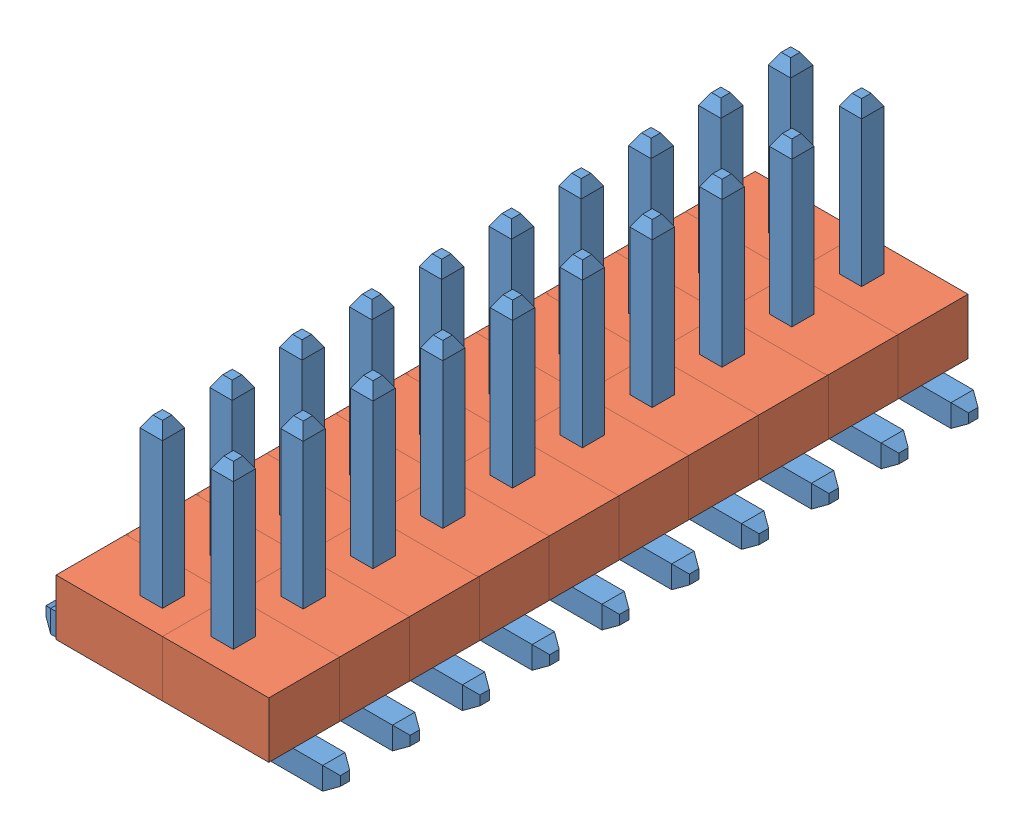
SolidWorks assembly Assem5, configuration Default. Lengths in mm.
Overall size (5.27 4.2 12.52).
60 component instances, 2 part files, 0 mates.
Components (placement in the parent):
- 1_27mm_single_pin_assembled-1: 1_27mm_single_pin_assembled [Default] at (-0.3615 -0.2189 0.4542) size (2.64 4.2 1.27)
  - 1_27mm_pin_right_angle-1: 1_27mm_pin_right_angle [Default] at (-0.7701 -1.6572 -0.2335) size (2.2 4.2 0.4)
  - 1_27mm_plastic_for_pin-1: 1_27mm_plastic_for_pin [Default] at (-0.4526 -1.4572 -0.2335) x (0 0 -1) z (1 0 0) size (1.27 1 1.91)
- 1_27mm_single_pin_assembled-2: 1_27mm_single_pin_assembled [Default] at (-0.3615 -0.2189 -0.7958) size (2.64 4.2 1.27)
  - 1_27mm_pin_right_angle-1: 1_27mm_pin_right_angle [Default] at (-0.7701 -1.6572 -0.2335) size (2.2 4.2 0.4)
  - 1_27mm_plastic_for_pin-1: 1_27mm_plastic_for_pin [Default] at (-0.4526 -1.4572 -0.2335) x (0 0 -1) z (1 0 0) size (1.27 1 1.91)
- 1_27mm_single_pin_assembled-3: 1_27mm_single_pin_assembled [Default] at (-0.3615 -0.2189 -2.0458) size (2.64 4.2 1.27)
  - 1_27mm_pin_right_angle-1: 1_27mm_pin_right_angle [Default] at (-0.7701 -1.6572 -0.2335) size (2.2 4.2 0.4)
  - 1_27mm_plastic_for_pin-1: 1_27mm_plastic_for_pin [Default] at (-0.4526 -1.4572 -0.2335) x (0 0 -1) z (1 0 0) size (1.27 1 1.91)
- 1_27mm_single_pin_assembled-4: 1_27mm_single_pin_assembled [Default] at (-0.3615 -0.2189 -3.2958) size (2.64 4.2 1.27)
  - 1_27mm_pin_right_angle-1: 1_27mm_pin_right_angle [Default] at (-0.7701 -1.6572 -0.2335) size (2.2 4.2 0.4)
  - 1_27mm_plastic_for_pin-1: 1_27mm_plastic_for_pin [Default] at (-0.4526 -1.4572 -0.2335) x (0 0 -1) z (1 0 0) size (1.27 1 1.91)
- 1_27mm_single_pin_assembled-5: 1_27mm_single_pin_assembled [Default] at (-0.3615 -0.2189 -4.5458) size (2.64 4.2 1.27)
  - 1_27mm_pin_right_angle-1: 1_27mm_pin_right_angle [Default] at (-0.7701 -1.6572 -0.2335) size (2.2 4.2 0.4)
  - 1_27mm_plastic_for_pin-1: 1_27mm_plastic_for_pin [Default] at (-0.4526 -1.4572 -0.2335) x (0 0 -1) z (1 0 0) size (1.27 1 1.91)
- 1_27mm_single_pin_assembled-6: 1_27mm_single_pin_assembled [Default] at (-0.3615 -0.2189 -5.7958) size (2.64 4.2 1.27)
  - 1_27mm_pin_right_angle-1: 1_27mm_pin_right_angle [Default] at (-0.7701 -1.6572 -0.2335) size (2.2 4.2 0.4)
  - 1_27mm_plastic_for_pin-1: 1_27mm_plastic_for_pin [Default] at (-0.4526 -1.4572 -0.2335) x (0 0 -1) z (1 0 0) size (1.27 1 1.91)
- 1_27mm_single_pin_assembled-7: 1_27mm_single_pin_assembled [Default] at (-0.3615 -0.2189 -7.0458) size (2.64 4.2 1.27)
  - 1_27mm_pin_right_angle-1: 1_27mm_pin_right_angle [Default] at (-0.7701 -1.6572 -0.2335) size (2.2 4.2 0.4)
  - 1_27mm_plastic_for_pin-1: 1_27mm_plastic_for_pin [Default] at (-0.4526 -1.4572 -0.2335) x (0 0 -1) z (1 0 0) size (1.27 1 1.91)
- 1_27mm_single_pin_assembled-8: 1_27mm_single_pin_assembled [Default] at (-0.3615 -0.2189 -8.2958) size (2.64 4.2 1.27)
  - 1_27mm_pin_right_angle-1: 1_27mm_pin_right_angle [Default] at (-0.7701 -1.6572 -0.2335) size (2.2 4.2 0.4)
  - 1_27mm_plastic_for_pin-1: 1_27mm_plastic_for_pin [Default] at (-0.4526 -1.4572 -0.2335) x (0 0 -1) z (1 0 0) size (1.27 1 1.91)
- 1_27mm_single_pin_assembled-9: 1_27mm_single_pin_assembled [Default] at (-0.3615 -0.2189 -9.5458) size (2.64 4.2 1.27)
  - 1_27mm_pin_right_angle-1: 1_27mm_pin_right_angle [Default] at (-0.7701 -1.6572 -0.2335) size (2.2 4.2 0.4)
  - 1_27mm_plastic_for_pin-1: 1_27mm_plastic_for_pin [Default] at (-0.4526 -1.4572 -0.2335) x (0 0 -1) z (1 0 0) size (1.27 1 1.91)
- 1_27mm_single_pin_assembled-10: 1_27mm_single_pin_assembled [Default] at (-0.3615 -0.2189 -10.7958) size (2.64 4.2 1.27)
  - 1_27mm_pin_right_angle-1: 1_27mm_pin_right_angle [Default] at (-0.7701 -1.6572 -0.2335) size (2.2 4.2 0.4)
  - 1_27mm_plastic_for_pin-1: 1_27mm_plastic_for_pin [Default] at (-0.4526 -1.4572 -0.2335) x (0 0 -1) z (1 0 0) size (1.27 1 1.91)
- 1_27mm_single_pin_assembled-11: 1_27mm_single_pin_assembled [Default] at (-3.1717 -0.2189 -10.0128) x (-1 0 0) z (0 0 -1) size (2.64 4.2 1.27)
  - 1_27mm_pin_right_angle-1: 1_27mm_pin_right_angle [Default] at (-0.7701 -1.6572 -0.2335) size (2.2 4.2 0.4)
  - 1_27mm_plastic_for_pin-1: 1_27mm_plastic_for_pin [Default] at (-0.4526 -1.4572 -0.2335) x (0 0 -1) z (1 0 0) size (1.27 1 1.91)
- 1_27mm_single_pin_assembled-12: 1_27mm_single_pin_assembled [Default] at (-3.1717 -0.2189 -8.7628) x (-1 0 0) z (0 0 -1) size (2.64 4.2 1.27)
  - 1_27mm_pin_right_angle-1: 1_27mm_pin_right_angle [Default] at (-0.7701 -1.6572 -0.2335) size (2.2 4.2 0.4)
  - 1_27mm_plastic_for_pin-1: 1_27mm_plastic_for_pin [Default] at (-0.4526 -1.4572 -0.2335) x (0 0 -1) z (1 0 0) size (1.27 1 1.91)
- 1_27mm_single_pin_assembled-13: 1_27mm_single_pin_assembled [Default] at (-3.1717 -0.2189 -11.2628) x (-1 0 0) z (0 0 -1) size (2.64 4.2 1.27)
  - 1_27mm_pin_right_angle-1: 1_27mm_pin_right_angle [Default] at (-0.7701 -1.6572 -0.2335) size (2.2 4.2 0.4)
  - 1_27mm_plastic_for_pin-1: 1_27mm_plastic_for_pin [Default] at (-0.4526 -1.4572 -0.2335) x (0 0 -1) z (1 0 0) size (1.27 1 1.91)
- 1_27mm_single_pin_assembled-14: 1_27mm_single_pin_assembled [Default] at (-3.1717 -0.2189 -3.7628) x (-1 0 0) z (0 0 -1) size (2.64 4.2 1.27)
  - 1_27mm_pin_right_angle-1: 1_27mm_pin_right_angle [Default] at (-0.7701 -1.6572 -0.2335) size (2.2 4.2 0.4)
  - 1_27mm_plastic_for_pin-1: 1_27mm_plastic_for_pin [Default] at (-0.4526 -1.4572 -0.2335) x (0 0 -1) z (1 0 0) size (1.27 1 1.91)
- 1_27mm_single_pin_assembled-15: 1_27mm_single_pin_assembled [Default] at (-3.1717 -0.2189 -5.0128) x (-1 0 0) z (0 0 -1) size (2.64 4.2 1.27)
  - 1_27mm_pin_right_angle-1: 1_27mm_pin_right_angle [Default] at (-0.7701 -1.6572 -0.2335) size (2.2 4.2 0.4)
  - 1_27mm_plastic_for_pin-1: 1_27mm_plastic_for_pin [Default] at (-0.4526 -1.4572 -0.2335) x (0 0 -1) z (1 0 0) size (1.27 1 1.91)
- 1_27mm_single_pin_assembled-16: 1_27mm_single_pin_assembled [Default] at (-3.1717 -0.2189 -6.2628) x (-1 0 0) z (0 0 -1) size (2.64 4.2 1.27)
  - 1_27mm_pin_right_angle-1: 1_27mm_pin_right_angle [Default] at (-0.7701 -1.6572 -0.2335) size (2.2 4.2 0.4)
  - 1_27mm_plastic_for_pin-1: 1_27mm_plastic_for_pin [Default] at (-0.4526 -1.4572 -0.2335) x (0 0 -1) z (1 0 0) size (1.27 1 1.91)
- 1_27mm_single_pin_assembled-17: 1_27mm_single_pin_assembled [Default] at (-3.1717 -0.2189 -7.5128) x (-1 0 0) z (0 0 -1) size (2.64 4.2 1.27)
  - 1_27mm_pin_right_angle-1: 1_27mm_pin_right_angle [Default] at (-0.7701 -1.6572 -0.2335) size (2.2 4.2 0.4)
  - 1_27mm_plastic_for_pin-1: 1_27mm_plastic_for_pin [Default] at (-0.4526 -1.4572 -0.2335) x (0 0 -1) z (1 0 0) size (1.27 1 1.91)
- 1_27mm_single_pin_assembled-18: 1_27mm_single_pin_assembled [Default] at (-3.1717 -0.2189 -0.0128) x (-1 0 0) z (0 0 -1) size (2.64 4.2 1.27)
  - 1_27mm_pin_right_angle-1: 1_27mm_pin_right_angle [Default] at (-0.7701 -1.6572 -0.2335) size (2.2 4.2 0.4)
  - 1_27mm_plastic_for_pin-1: 1_27mm_plastic_for_pin [Default] at (-0.4526 -1.4572 -0.2335) x (0 0 -1) z (1 0 0) size (1.27 1 1.91)
- 1_27mm_single_pin_assembled-19: 1_27mm_single_pin_assembled [Default] at (-3.1717 -0.2189 -2.5128) x (-1 0 0) z (0 0 -1) size (2.64 4.2 1.27)
  - 1_27mm_pin_right_angle-1: 1_27mm_pin_right_angle [Default] at (-0.7701 -1.6572 -0.2335) size (2.2 4.2 0.4)
  - 1_27mm_plastic_for_pin-1: 1_27mm_plastic_for_pin [Default] at (-0.4526 -1.4572 -0.2335) x (0 0 -1) z (1 0 0) size (1.27 1 1.91)
- 1_27mm_single_pin_assembled-20: 1_27mm_single_pin_assembled [Default] at (-3.1717 -0.2189 -1.2628) x (-1 0 0) z (0 0 -1) size (2.64 4.2 1.27)
  - 1_27mm_pin_right_angle-1: 1_27mm_pin_right_angle [Default] at (-0.7701 -1.6572 -0.2335) size (2.2 4.2 0.4)
  - 1_27mm_plastic_for_pin-1: 1_27mm_plastic_for_pin [Default] at (-0.4526 -1.4572 -0.2335) x (0 0 -1) z (1 0 0) size (1.27 1 1.91)
